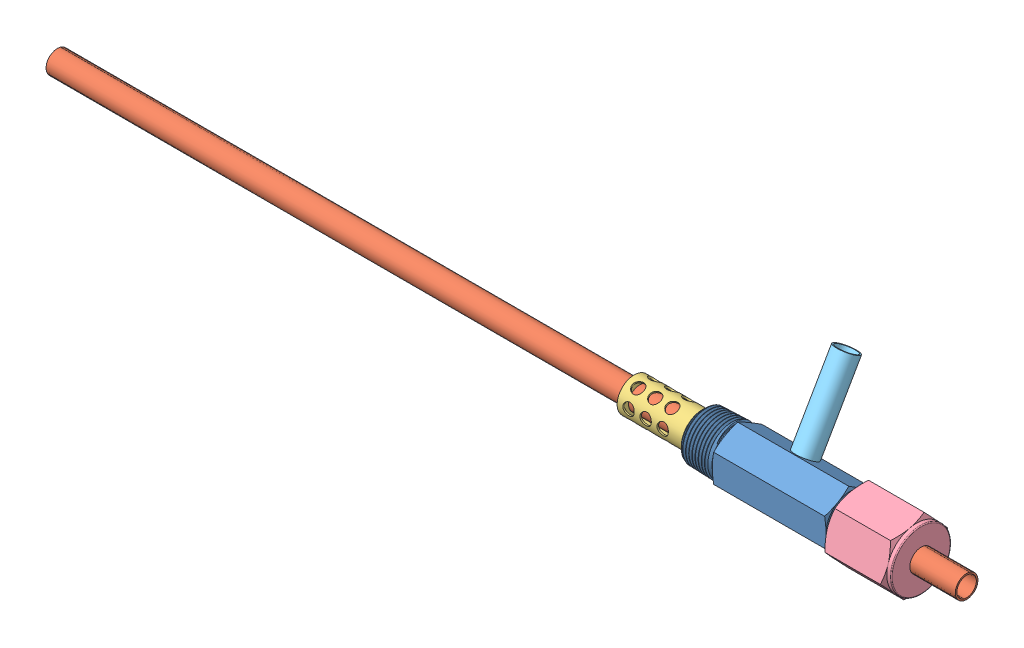
SolidWorks assembly Assem1, configuration Default. Lengths in mm.
Overall size (508 78.58 57.83).
5 component instances, 5 part files, 9 mates.
Components (placement in the parent):
- 48805K882_Precision Extreme-Pressure 316 Stainless Steel Fitting-1: 48805K882_Precision Extreme-Pressure 316 Stainless Steel Fitting [48805K882] at origin size (102.37 31.16 29.09)
- dip straw tube-1: dip straw tube [Default] at (96.8375 0 0) x (0 0.859533 -0.511081) z (0 0.511081 0.859533) size (12.7 508 12.7)
- diffuser-1: diffuser [Default] at (-38.1 0 0) x (0 -0.997499 0.070675) z (0 0.070675 0.997499) size (19.05 50.8 19.05)
- 48805K725_Precision Extreme-Pressure 316 Stainless Steel Fitting-1: 48805K725_Precision Extreme-Pressure 316 Stainless Steel Fitting [48805K725] at (53.1812 0 0) x (0 -0.2916 -0.95654) z (1 0 0) size (33.34 38.49 37.12)
- nitrogen inlet tube-1: nitrogen inlet tube [Default] at (0 7.5615 -4.3656) x (0 0.866025 -0.5) z (0.97896 0.102027 0.176716) size (50.8 12.7 12.7)
Mates (geometry in assembly coordinates):
- Coincident1: coordinate: point of 48805K882_Precision Extreme-Pressure 316 Stainless Steel Fitting-1
- Concentric1: concentric anti-aligned: cylinder of 48805K882_Precision Extreme-Pressure 316 Stainless Steel Fitting-1 through (51.1849 0 0) axis (-1 0 0) radius 9.525; cylinder of dip straw tube-1 through (-411.1625 0 0) axis (1 0 0) radius 6.35
- Concentric2: concentric aligned: cylinder of dip straw tube-1 through (-411.1625 0 0) axis (1 0 0) radius 6.35; cylinder of diffuser-1 through (-38.1 0 0) axis (1 0 0) radius 6.35
- Distance1: distance = 12.7 mm anti-aligned: plane of 48805K882_Precision Extreme-Pressure 316 Stainless Steel Fitting-1 through (-50.8 0 0) normal (-1 0 0); plane of diffuser-1 through (-38.1 8.6144 -0.6104) normal (1 0 0)
- Concentric3: concentric anti-aligned: cylinder of 48805K882_Precision Extreme-Pressure 316 Stainless Steel Fitting-1 through (51.1849 0 0) axis (-1 0 0) radius 9.525; cylinder of 48805K725_Precision Extreme-Pressure 316 Stainless Steel Fitting-1 through (68.8975 0 0) axis (1 0 0) radius 16.6687
- Distance2: distance = 15.875 mm anti-aligned: plane of 48805K725_Precision Extreme-Pressure 316 Stainless Steel Fitting-1 through (34.925 32.477 7.5255) normal (-1 0 0); plane of 48805K882_Precision Extreme-Pressure 316 Stainless Steel Fitting-1 through (50.8 0 0) normal (1 0 0)
- Distance3: distance = 25.4 mm aligned: plane of dip straw tube-1 through (96.8375 0 0) normal (1 0 0); plane of 48805K725_Precision Extreme-Pressure 316 Stainless Steel Fitting-1 through (71.4375 32.477 7.5255) normal (1 0 0)
- Concentric4: concentric anti-aligned: cylinder of 48805K882_Precision Extreme-Pressure 316 Stainless Steel Fitting-1 through (0 11.6859 -6.7469) axis (0 0.866025 -0.5) radius 6.35; cylinder of nitrogen inlet tube-1 through (0 51.5556 -29.7656) axis (0 -0.866025 0.5) radius 6.35
- Distance4: distance = 4.7625 mm anti-aligned: plane of nitrogen inlet tube-1 through (0 7.5615 -4.3656) normal (0 -0.866025 0.5); plane of 48805K882_Precision Extreme-Pressure 316 Stainless Steel Fitting-1 through (31.75 7.7906 -13.4938) normal (0 0.866025 -0.5)
